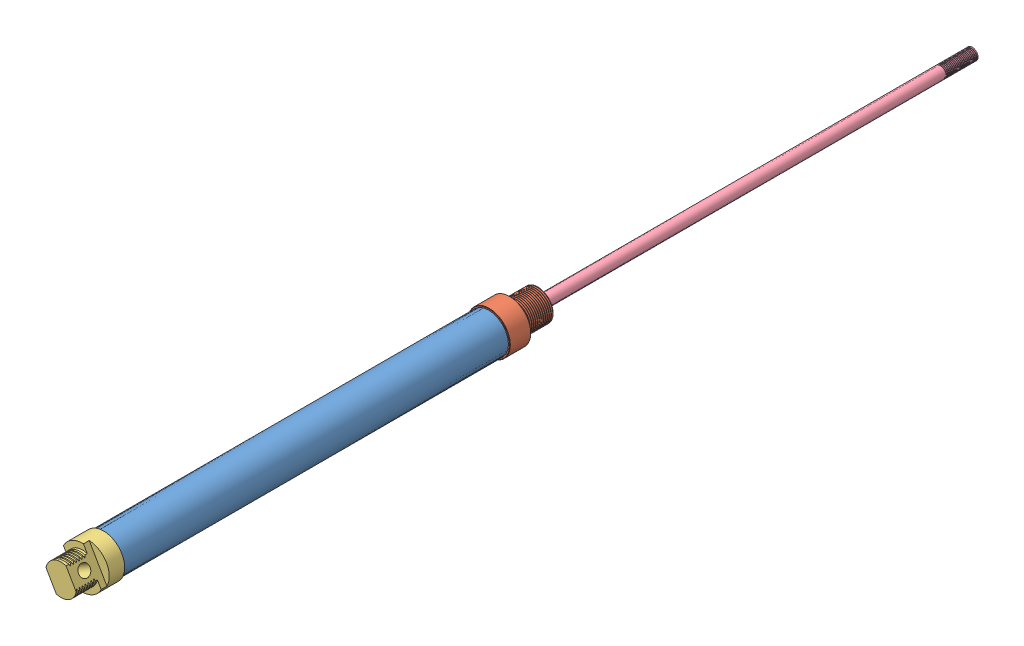
SolidWorks assembly piston, configuration Default. Lengths in mm.
Overall size (30.12 30.17 473).
4 component instances, 4 part files, 7 mates.
Components (placement in the parent):
- piston#3-1: piston#3 [Default] at (118.4318 166.4605 127.8066) size (20.5 20.5 200)
- piston #1-1: piston #1 [Default] at (118.4318 166.4605 116.8066) size (22 22 25.57)
- piston #2-1: piston #2 [Default] at (118.4318 166.4605 335.8066) x (0.866621 0.498966 0) z (0 0 -1) size (22 22.15 22)
- piston #4-1: piston #4 [Default] at (118.4318 166.4605 -123.1934) x (-0.418441 0.908244 0) z (0 0 1) size (6 6 246)
Mates (geometry in assembly coordinates):
- Coincident1: coincident anti-aligned: plane of piston#3-1 through (118.4318 166.4605 327.8066) normal (0 0 1); plane of piston #2-1 through (118.4318 166.4605 327.8066) normal (0 0 -1)
- Concentric1: concentric anti-aligned: circle of piston#3-1; circle of piston #2-1
- Coincident2: coincident anti-aligned: plane of piston#3-1 through (118.4318 166.4605 127.8066) normal (0 0 -1); plane of piston #1-1 through (118.4318 166.4605 127.8066) normal (0 0 1)
- Concentric2: concentric anti-aligned: circle of piston#3-1; circle of piston #1-1
- Concentric4: concentric anti-aligned: circle of piston #1-1; circle of piston #4-1
- LimitDistance1: limit distance = 205 mm anti-aligned: plane of piston #2-1 through (118.4318 166.4605 327.8066) normal (0 0 -1); plane of piston #4-1 through (118.4318 166.4605 122.8066) normal (0 0 1)
- Parallel1: parallel aligned: line of piston #1-1 through (122.7909 158.4419 122.3066) axis (0.477606 -0.878574 0); line of piston #2-1 through (123.0185 158.0232 332.8066) axis (0.477606 -0.878574 0)
